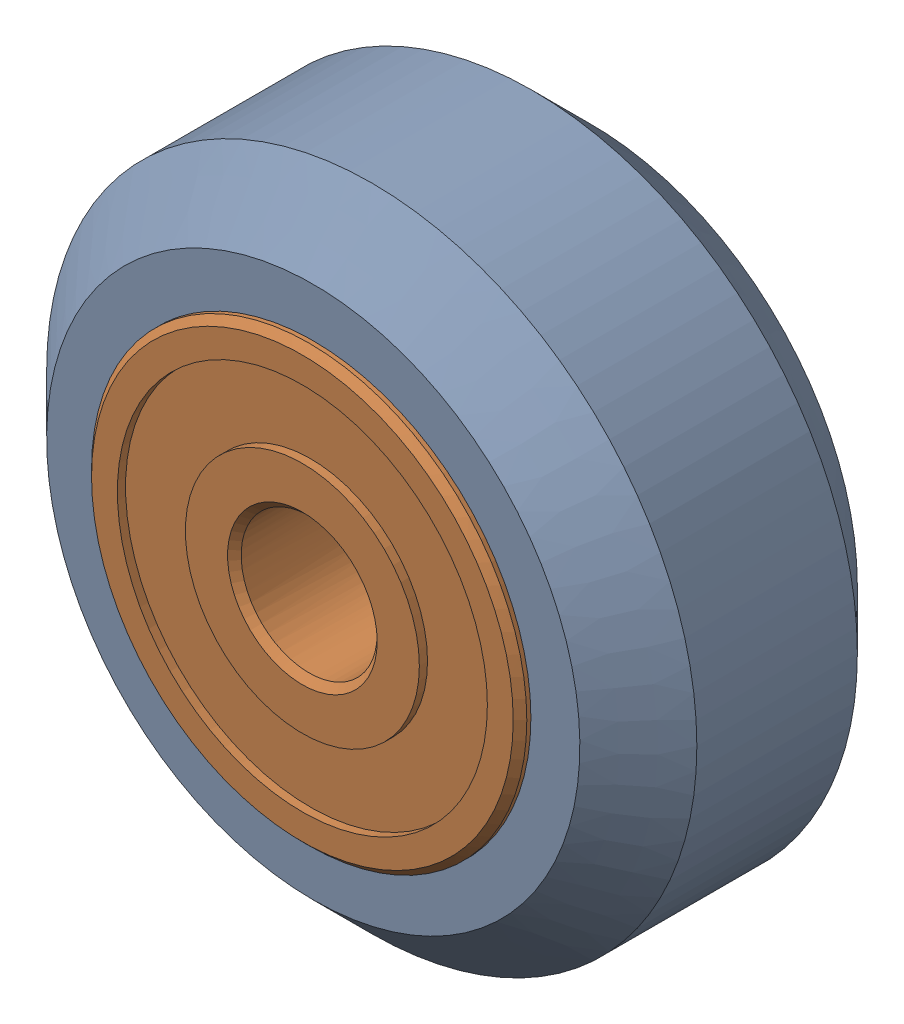
SolidWorks assembly Xtreme Solid V Wheel Assembly_5, configuration Default. Lengths in mm.
Overall size (23.9 23.9 11).
3 component instances, 2 part files, 0 mates.
Components (placement in the parent):
- Xtreme Solid V Wheel-1: Xtreme Solid V Wheel [Default] at (-84.85 -55.79 30) x (0 0 1) z (-1 0 0) size (10.2 23.9 23.9)
- Wheel+Kit+-+5x16x5mm+Sealed+Radial+Ball+Bearing.step.f3d-1: Wheel+Kit+-+5x16x5mm+Sealed+Radial+Ball+Bearing.step.f3d [Default] at (-84.85 -55.79 30) x (0 1 0) z (-1 0 0) size (16 5 16)
- Wheel+Kit+-+5x16x5mm+Sealed+Radial+Ball+Bearing.step.f3d-2: Wheel+Kit+-+5x16x5mm+Sealed+Radial+Ball+Bearing.step.f3d [Default] at (-84.85 -55.79 30) x (0 1 0) z (1 0 0) size (16 5 16)
